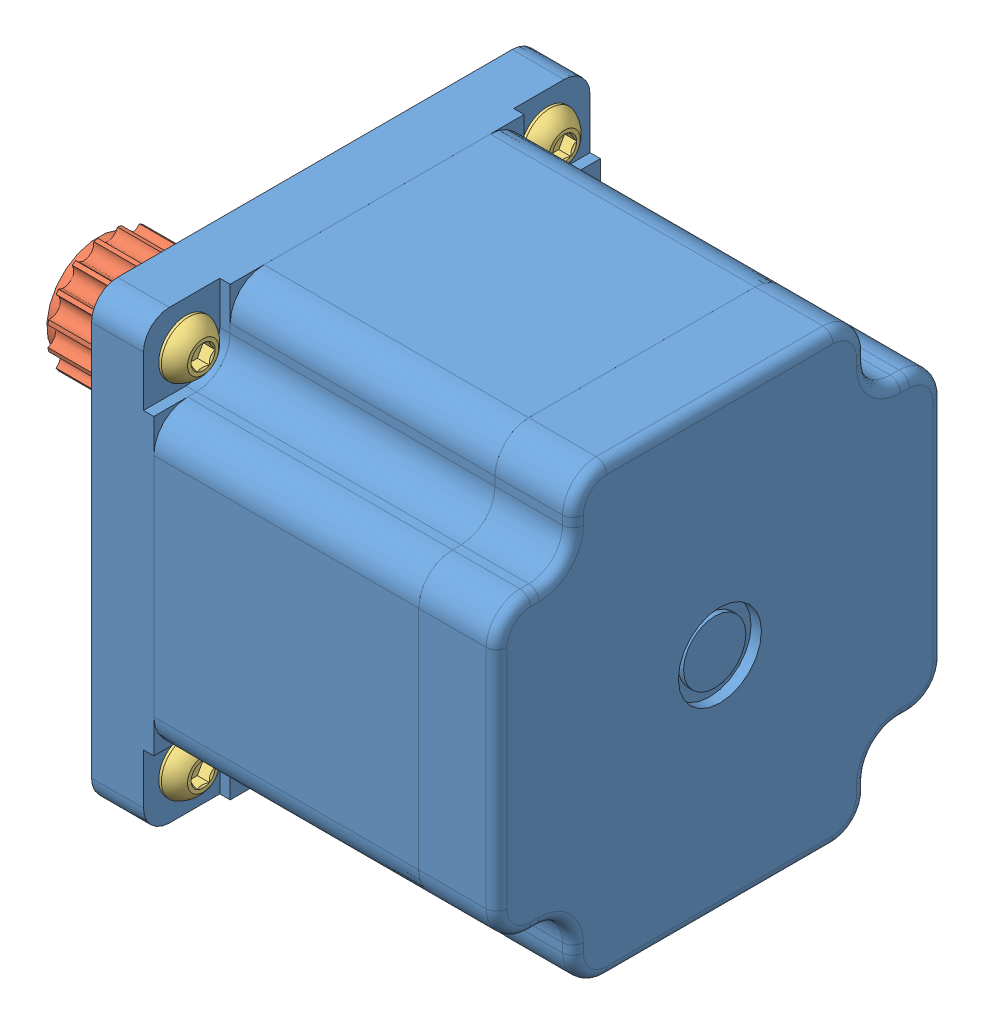
SolidWorks assembly 004 - Injector Motor, configuration Default. Lengths in mm.
Overall size (119.6 86 86).
8 component instances, 4 part files, 15 mates.
Components (placement in the parent):
- SP - NEMA34 Motor - Phidgets 3335_0-1: SP - NEMA34 Motor - Phidgets 3335_0 [Default] at origin size (116.6 86 86)
- SP - 16TxHTD5 Pulley - Phidgets TRM4125_0-1: SP - 16TxHTD5 Pulley - Phidgets TRM4125_0 [Default] at (-60.8043 30.4995 43) x (1 0 0) z (0 -1 0) size (28 28 28)
- SP - M6x14 BHCS - McMaster-Carr 91239A319-1: SP - M6x14 BHCS - McMaster-Carr 91239A319 [91239A319] at (-17.1543 65.2995 77.8) x (0 -0.48691 -0.873452) z (1 0 0) size (10.5 10.5 17.89)
- SP - M6x14 BHCS - McMaster-Carr 91239A319-2: SP - M6x14 BHCS - McMaster-Carr 91239A319 [91239A319] at (-17.1543 65.2995 8.2) x (0 -0.48691 -0.873452) z (1 0 0) size (10.5 10.5 17.89)
- SP - M6x14 BHCS - McMaster-Carr 91239A319-3: SP - M6x14 BHCS - McMaster-Carr 91239A319 [91239A319] at (-17.1543 -4.3005 77.8) x (0 -0.48691 -0.873452) z (1 0 0) size (10.5 10.5 17.89)
- SP - M6x14 BHCS - McMaster-Carr 91239A319-4: SP - M6x14 BHCS - McMaster-Carr 91239A319 [91239A319] at (-17.1543 -4.3005 8.2) x (0 -0.48691 -0.873452) z (1 0 0) size (10.5 10.5 17.89)
- SP - M4x6 CPSS - McMaster-Carr 91390A112-1: SP - M4x6 CPSS - McMaster-Carr 91390A112 [91390A112] at (-47.6543 30.4995 54.3293) size (4.11 4.62 6.7)
- SP - M4x6 CPSS - McMaster-Carr 91390A112-2: SP - M4x6 CPSS - McMaster-Carr 91390A112 [91390A112] at (-47.6543 41.8287 43) x (0.859389 0 0.511322) z (0 1 0) size (4.11 4.62 6.7)
Mates (geometry in assembly coordinates):
- Concentric1: concentric anti-aligned: cylinder of SP - NEMA34 Motor - Phidgets 3335_0-1 through (-69.0543 30.4995 43) axis (1 0 0) radius 7; cylinder of SP - 16TxHTD5 Pulley - Phidgets TRM4125_0-1 through (-60.8043 30.4995 43) axis (-1 0 0) radius 6.35
- Perpendicular1: perpendicular: plane of SP - NEMA34 Motor - Phidgets 3335_0-1 through (-44.0543 35.1495 31.5013) normal (0 1 0); axis of SP - 16TxHTD5 Pulley - Phidgets TRM4125_0-1 through (-47.6543 44.4019 43) axis (0 -1 0)
- Coincident2: coincident anti-aligned: plane of SP - NEMA34 Motor - Phidgets 3335_0-1 through (-44.0543 0 0) normal (-1 0 0); plane of SP - 16TxHTD5 Pulley - Phidgets TRM4125_0-1 through (-44.0543 30.4995 43) normal (1 0 0)
- Concentric2: concentric aligned: cylinder of SP - NEMA34 Motor - Phidgets 3335_0-1 through (-10.4543 65.2995 77.8) axis (-1 0 0) radius 3.25; cylinder of SP - M6x14 BHCS - McMaster-Carr 91239A319-1 through (-34.4543 65.2995 77.8) axis (-1 0 0) radius 3
- Coincident3: coincident anti-aligned: plane of SP - NEMA34 Motor - Phidgets 3335_0-1 through (-20.4543 65.2995 77.8) normal (1 0 0); plane of SP - M6x14 BHCS - McMaster-Carr 91239A319-1 through (-20.4543 60.7138 80.3563) normal (-1 0 0)
- Concentric3: concentric aligned: cylinder of SP - NEMA34 Motor - Phidgets 3335_0-1 through (-10.4543 -4.3005 77.8) axis (-1 0 0) radius 3.25; cylinder of SP - M6x14 BHCS - McMaster-Carr 91239A319-3 through (-34.4543 -4.3005 77.8) axis (-1 0 0) radius 3
- Coincident4: coincident anti-aligned: plane of SP - NEMA34 Motor - Phidgets 3335_0-1 through (-20.4543 -4.3005 77.8) normal (1 0 0); plane of SP - M6x14 BHCS - McMaster-Carr 91239A319-3 through (-20.4543 -8.8862 80.3563) normal (-1 0 0)
- Concentric4: concentric aligned: cylinder of SP - NEMA34 Motor - Phidgets 3335_0-1 through (-10.4543 65.2995 8.2) axis (-1 0 0) radius 3.25; cylinder of SP - M6x14 BHCS - McMaster-Carr 91239A319-2 through (-34.4543 65.2995 8.2) axis (-1 0 0) radius 3
- Coincident5: coincident anti-aligned: plane of SP - NEMA34 Motor - Phidgets 3335_0-1 through (-20.4543 65.2995 8.2) normal (1 0 0); plane of SP - M6x14 BHCS - McMaster-Carr 91239A319-2 through (-20.4543 60.7138 10.7563) normal (-1 0 0)
- Coincident6: coincident anti-aligned: plane of SP - NEMA34 Motor - Phidgets 3335_0-1 through (-20.4543 -4.3005 8.2) normal (1 0 0); plane of SP - M6x14 BHCS - McMaster-Carr 91239A319-4 through (-20.4543 -8.8862 10.7563) normal (-1 0 0)
- Concentric5: concentric aligned: cylinder of SP - NEMA34 Motor - Phidgets 3335_0-1 through (-10.4543 -4.3005 8.2) axis (-1 0 0) radius 3.25; cylinder of SP - M6x14 BHCS - McMaster-Carr 91239A319-4 through (-34.4543 -4.3005 8.2) axis (-1 0 0) radius 3
- Concentric6: concentric anti-aligned: cylinder of SP - 16TxHTD5 Pulley - Phidgets TRM4125_0-1 through (-47.6543 30.4995 43) axis (0 0 -1) radius 1.65; cylinder of SP - M4x6 CPSS - McMaster-Carr 91390A112-1 through (-47.6543 30.4995 51.6585) axis (0 0 1) radius 2
- Tangent1: tangent aligned: cylinder of SP - 16TxHTD5 Pulley - Phidgets TRM4125_0-1 through (-60.8043 30.4995 43) axis (-1 0 0) radius 14; plane of SP - M4x6 CPSS - McMaster-Carr 91390A112-1 through (-47.6543 30.4995 57) normal (0 0 1)
- Concentric8: concentric anti-aligned: cylinder of SP - 16TxHTD5 Pulley - Phidgets TRM4125_0-1 through (-47.6543 30.4995 43) axis (0 -1 0) radius 1.65; cylinder of SP - M4x6 CPSS - McMaster-Carr 91390A112-2 through (-47.6543 39.158 43) axis (0 1 0) radius 2
- Tangent2: tangent aligned: cylinder of SP - 16TxHTD5 Pulley - Phidgets TRM4125_0-1 through (-60.8043 30.4995 43) axis (-1 0 0) radius 14; plane of SP - M4x6 CPSS - McMaster-Carr 91390A112-2 through (-47.6543 44.4995 43) normal (0 1 0)
